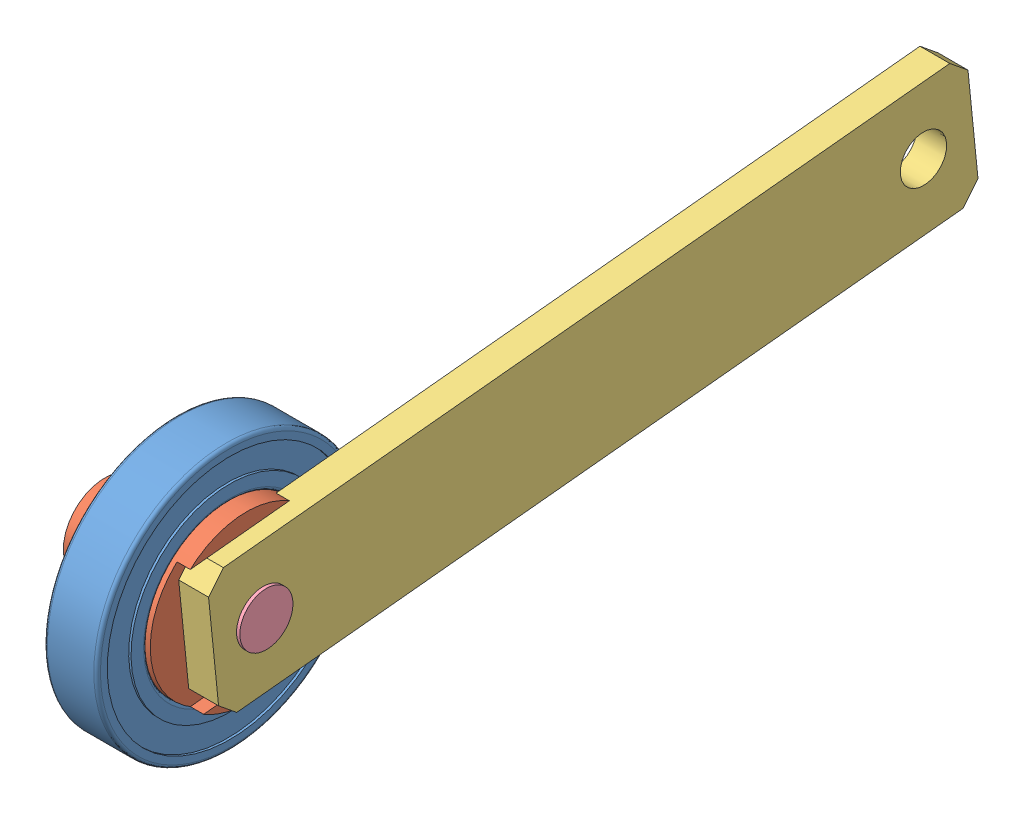
SolidWorks assembly 組合件4, configuration 預設. Lengths in mm.
Overall size (48.7 99.88 265.86).
4 component instances, 4 part files, 6 mates.
Components (placement in the parent):
- 9-1: 9 [Default] at (-8.9411 29.2974 127.9169) x (1 0 0) z (0 -0.292163 0.956369) size (16 80 80)
- 110303047-08-1: 110303047-08 [預設] at (-8.9411 29.2974 127.9169) x (0 -0.994932 -0.100553) z (0 -0.100553 0.994932) size (57 42.7 57)
- 11-1: 11 [Default] at (8.0589 39.3526 28.4238) x (0 0.100553 -0.994932) z (1 0 0) size (230 40 9)
- 110303047-10-1: 110303047-10 [預設] at (4.0589 29.2974 127.9169) x (0 -1 0) z (0 0 1) size (16 14 16)
Mates (geometry in assembly coordinates):
- 輪廓中心2: profile center aligned: plane of 110303047-08-1 through (-8.9411 4.4241 125.4031) normal (1 0 0); circle of 9-1
- 同軸心1: concentric anti-aligned: cylinder of 110303047-08-1 through (4.0589 29.2974 127.9169) axis (1 0 0) radius 7; cylinder of 11-1 through (17.0589 29.2974 127.9169) axis (-1 0 0) radius 7
- 重合/共線/共點2: coincident anti-aligned: plane of 110303047-08-1 through (8.0589 29.2974 127.9169) normal (1 0 0); plane of 11-1 through (8.0589 39.3526 28.4238) normal (-1 0 0)
- 重合/共線/共點4: coincident anti-aligned: plane of 110303047-08-1 through (8.0589 46.3302 158.2835) normal (0 -0.994932 -0.100553); plane of 11-1 through (17.0589 48.1905 139.8773) normal (0 0.994932 0.100553)
- 同軸心3: concentric anti-aligned: cylinder of 11-1 through (17.0589 29.2974 127.9169) axis (-1 0 0) radius 7; cylinder of 110303047-10-1 through (22.0703 29.2974 127.9169) axis (1 0 0) radius 7
- 重合/共線/共點6: coincident anti-aligned: plane of 11-1 through (17.0589 39.3526 28.4238) normal (1 0 0); plane of 110303047-10-1 through (17.0589 21.2974 127.9169) normal (-1 0 0)
